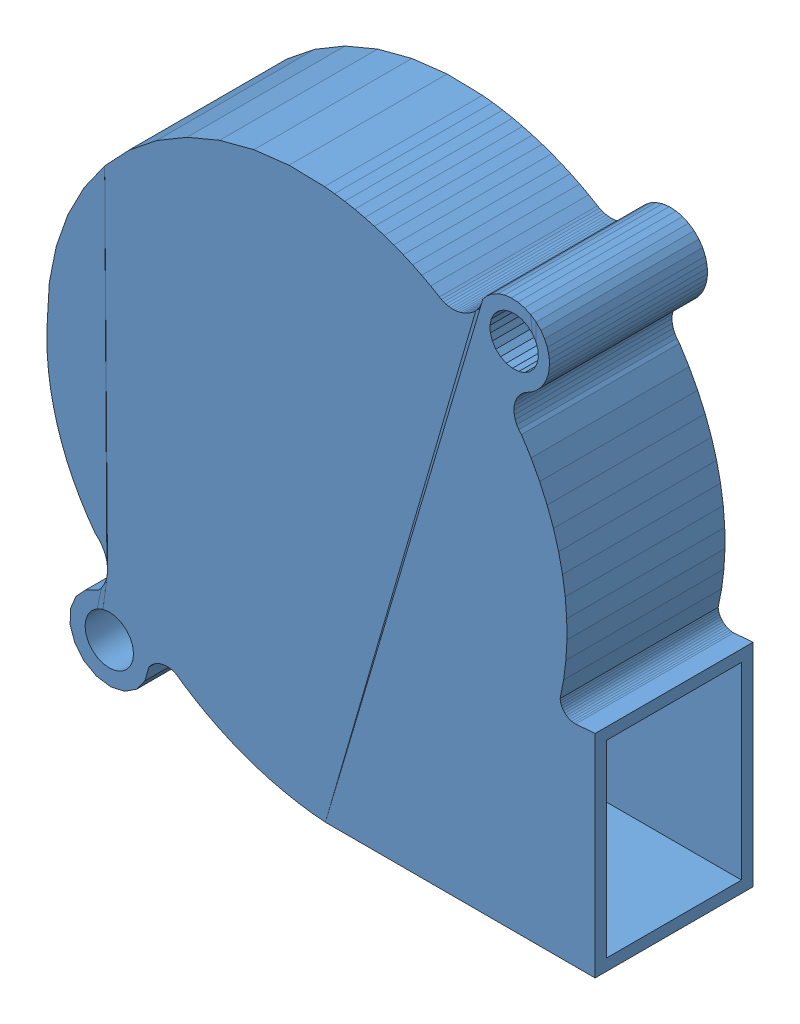
SolidWorks assembly fan with holder, configuration Default. Lengths in mm.
Overall size (52.32 54.01 15).
2 component instances, 1 part files, 0 mates.
Components (placement in the parent):
- fan-1: fan [Default] at (-123.2328 -1.9713 28.7167) size (52.32 54.01 15)
  - Component_3-1: Component_3 [Default] at (137.5608 37.6442 10.5) x (-1 0 0) z (0 0 1) size (52.32 54.01 15)
